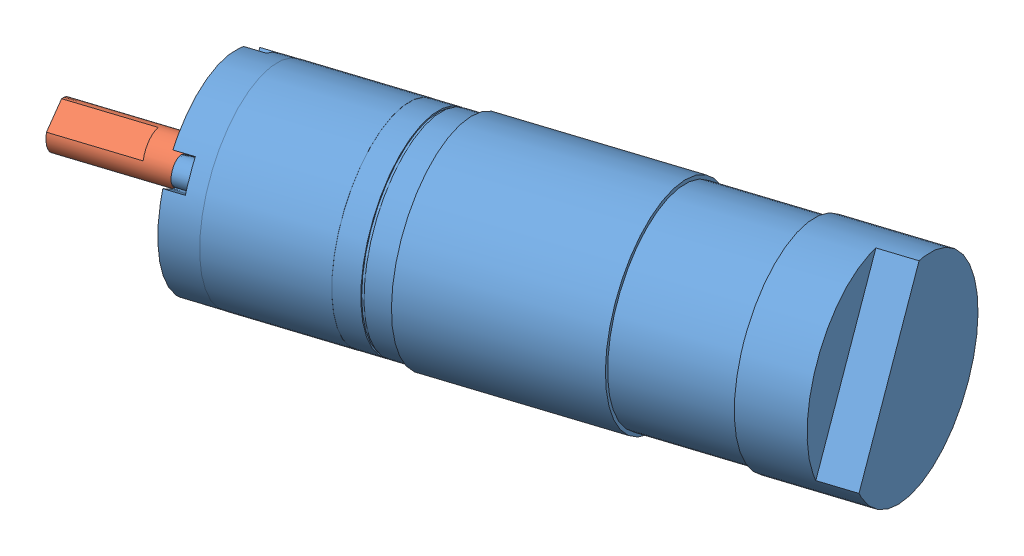
SolidWorks assembly DC planet geared motor, configuration Default. Lengths in mm.
Overall size (136.62 52.79 81.46).
2 component instances, 2 part files, 3 mates.
Components (placement in the parent):
- motor-1: motor [Default] at (-31.8628 68.735 102.3609) x (0.168703 -0.836716 0.521005) z (0.239325 0.547535 0.801829) size (37.3 109.75 37.3)
- shaft-1: shaft [Default] at (-25.6477 68.8038 100.4589) x (-0.253239 0.531568 -0.808273) z (0.146993 0.84695 0.510949) size (8 31.3 8)
Mates (geometry in assembly coordinates):
- Coincident1: coincident anti-aligned: plane of motor-1 through (-25.6477 68.8038 100.4589) normal (-0.956171 -0.010582 0.292618); plane of shaft-1 through (-25.6477 68.8038 100.4589) normal (0.956171 0.010582 -0.292618)
- Coincident2: coincident anti-aligned: plane of motor-1 through (-25.6477 68.8038 100.4589) normal (-0.956171 -0.010582 0.292618); plane of shaft-1 through (-25.6477 68.8038 100.4589) normal (0.956171 0.010582 -0.292618)
- Concentric1: concentric aligned: circle of motor-1; circle of shaft-1
